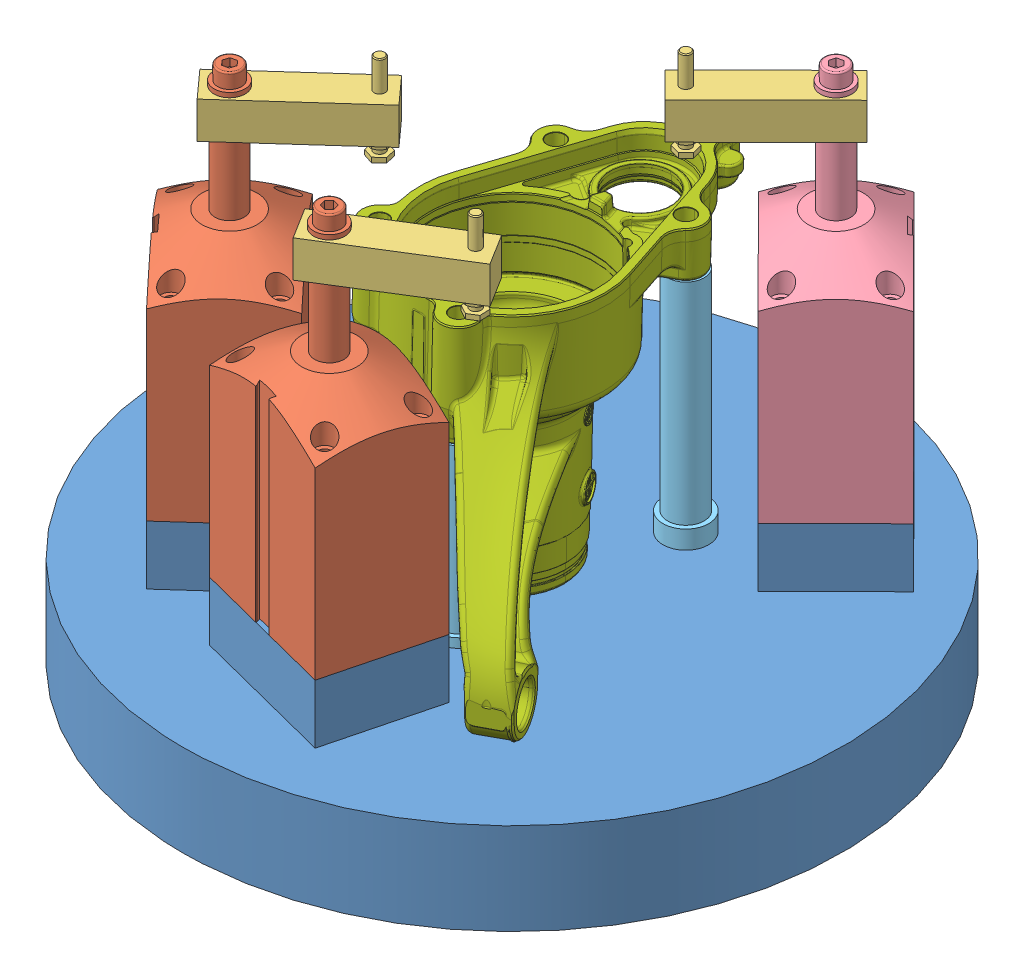
SolidWorks assembly Montagem placa, configuration Default. Lengths in mm.
Overall size (360 277.65 360).
17 component instances, 7 part files, 17 mates.
Components (placement in the parent):
- Base-1: Base [Default] at (99.4646 136.0716 348.7384) size (360 82.15 360)
- Subconjunto Aperto 1875206CCW-1: Subconjunto Aperto 1875206CCW [Default] at (3.4884 169.0481 385.0001) x (0.968681 0 0.24831) z (0 1 0) size (92.86 103.98 195.5) (flexible)
  - 1875206BCCW.stp-1: 1875206BCCW.stp [Default] at (115.4005 -41.7141 238.6721) size (80.1 79.39 189.5)
  - 0187526.stp-2: 0187526.stp [Default] at (115.4005 -41.7141 228.1721) x (0.690608 0.723229 0) z (0 0 1) size (78 20 47.65)
- Subconjunto Aperto 1875206CCW-2: Subconjunto Aperto 1875206CCW [Default] at (-35.7403 169.0481 300.3587) x (0.668982 0 0.743278) z (0 1 0) size (80.1 115.34 195.5) (flexible)
  - 1875206BCCW.stp-1: 1875206BCCW.stp [Default] at (115.4005 -41.7141 238.6721) size (80.1 79.39 189.5)
  - 0187526.stp-2: 0187526.stp [Default] at (115.4005 -41.7141 228.1721) x (0 1 0) z (0 0 1) size (78 20 47.65)
- Subconjunto Aperto 1875106CW-2: Subconjunto Aperto 1875106CW [Default] at (264.6171 161.2874 161.5895) x (-0.70491 0 -0.709297) z (0 1 0) size (80.1 115.34 195.5) (flexible)
  - 1875106BCW.stp-1: 1875106BCW.stp [Default] at (0.7105 124.0841 246.4327) size (80.1 79.39 189.5)
  - 0187526.stp-3: 0187526.stp [Default] at (0.7105 124.0841 235.9327) x (0 1 0) z (0 0 1) size (78 20 47.65)
- Cilindro de apoio-4: Cilindro de apoio [Apoio menor com pino] at (119.3186 181.0716 397.8794) x (0.433473 0 -0.901166) z (0 -1 0) size (25 25 99)
- Cilindro de apoio-5: Cilindro de apoio [Apoio menor sem pino] at (53.5656 186.0716 375.2384) x (0.949918 0 -0.3125) z (0 -1 0) size (25 25 111.5)
- Cilindro de apoio-6: Cilindro de apoio [Apoio maior sem pino] at (134.9646 186.0716 289.4384) x (0.949918 0 -0.3125) z (0 -1 0) size (25 25 142.5)
- Cilindro de apoio-7: Cilindro de apoio [Apoio auxiliar com pino] at (63.9646 181.0716 289.4384) x (0.081497 0 -0.996674) z (0 -1 0) size (25 25 129.95)
- Pino de posicionamento-1: Pino de posicionamento [Pino Maior] at (63.9646 259.5716 289.4384) x (0 1 0) z (0.537245 0 0.843427) size (65 15 15)
- Pino de posicionamento-2: Pino de posicionamento [Pino Menor] at (119.3186 224.8216 397.8794) x (0 1 0) z (0.999678 0 0.02537) size (66 15 15)
- Peça do cliente-2: Peça do cliente [Default] at (99.4646 336.0716 348.7384) x (-1 0 0) z (0 -1 0) size (175.56 233.49 149.01)
Mates (geometry in assembly coordinates):
- Concentric8: concentric anti-aligned: cylinder of Cilindro de apoio-7 through (63.9646 176.9295 289.4384) axis (0 1 0) radius 5; cylinder of Pino de posicionamento-1 through (63.9646 259.5716 289.4384) axis (0 -1 0) radius 5
- Concentric9: concentric anti-aligned: cylinder of Cilindro de apoio-4 through (119.3186 176.9295 397.8794) axis (0 1 0) radius 5; cylinder of Pino de posicionamento-2 through (119.3186 224.8216 397.8794) axis (0 -1 0) radius 5
- Coincident21: coincident anti-aligned: plane of Cilindro de apoio-4 through (128.3302 280.0716 402.2142) normal (0 1 0); plane of Peça do cliente-2 through (119.3186 280.0716 397.8794) normal (0 -1 0)
- Coincident22: coincident anti-aligned: plane of Cilindro de apoio-6 through (138.0896 311.0716 298.9376) normal (0 1 0); plane of Peça do cliente-2 through (134.9646 311.0716 289.4384) normal (0 -1 0)
- Concentric12: concentric anti-aligned: cylinder of Cilindro de apoio-6 through (134.9646 186.0716 289.4384) axis (0 -1 0) radius 10; cylinder of Peça do cliente-2 through (134.9646 306.3703 289.4384) axis (0 1 0) radius 4.75
- Concentric13: concentric anti-aligned: cylinder of Cilindro de apoio-7 through (63.9646 181.0716 289.4384) axis (0 -1 0) radius 10; cylinder of Peça do cliente-2 through (63.9646 306.3703 289.4384) axis (0 1 0) radius 4.75
- Concentric14: concentric anti-aligned: cylinder of Cilindro de apoio-5 through (53.5656 186.0716 375.2384) axis (0 -1 0) radius 10; cylinder of Peça do cliente-2 through (53.5656 274.1773 375.2384) axis (0 1 0) radius 4.5
- Concentric15: concentric anti-aligned: cylinder of Cilindro de apoio-4 through (119.3186 181.0716 397.8794) axis (0 -1 0) radius 10; cylinder of Peça do cliente-2 through (119.3186 274.1773 397.8794) axis (0 1 0) radius 4.5
- Concentric19: concentric anti-aligned: cylinder of Base-1 through (99.4646 186.0716 348.7384) axis (0 -1 0) radius 180; cylinder of Peça do cliente-2 through (99.4646 258.6716 348.7384) axis (0 1 0) radius 14.605
- Parallel3: parallel aligned: line of Peça do cliente-2 through (99.4646 336.0716 348.7384) axis (0 0 -1)
- Lock1: lock: unknown of Base-1; unknown of Subconjunto Aperto 1875206CCW-1/1875206BCCW.stp-1
- Lock2: lock: unknown of Base-1; unknown of Subconjunto Aperto 1875206CCW-2/1875206BCCW.stp-1
- Lock3: lock: unknown of Base-1; unknown of Subconjunto Aperto 1875106CW-2/1875106BCW.stp-1
- Coincident27: coincident anti-aligned: plane of Base-1 through (63.9646 181.0716 289.4384) normal (0 1 0); plane of Cilindro de apoio-7 through (76.423 181.0716 290.4572) normal (0 -1 0)
- Coincident28: coincident anti-aligned: plane of Base-1 through (119.3186 181.0716 397.8794) normal (0 1 0); plane of Cilindro de apoio-4 through (130.5831 181.0716 403.2979) normal (0 -1 0)
- Coincident29: coincident aligned: cone of Pino de posicionamento-1 through (63.9646 314.5716 289.4384) axis (0 1 0); circle of Peça do cliente-2
- Coincident30: coincident aligned: cone of Pino de posicionamento-2 through (119.3186 280.8216 397.8794) axis (0 1 0); circle of Peça do cliente-2
